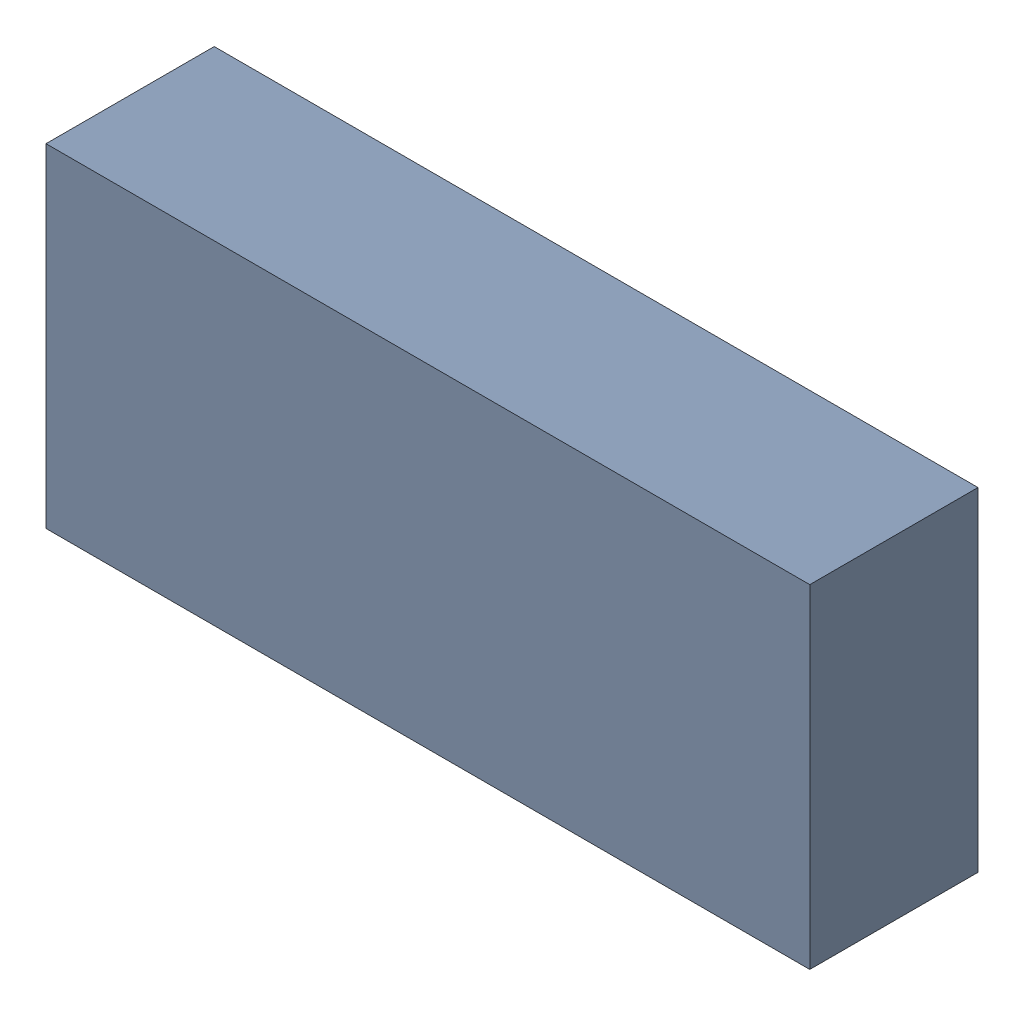
SolidWorks assembly 6327398656, configuration Default. Lengths in mm.
Overall size (1.15 0.5 0.25).
2 component instances, 1 part files, 0 mates.
Components (placement in the parent):
- 6701982208-1:  [Default] at (27.7 14.8 0) (suppressed, hidden)
- Extruded-19-1: Extruded-19 [Default] at origin size (1.15 0.5 0.25)
